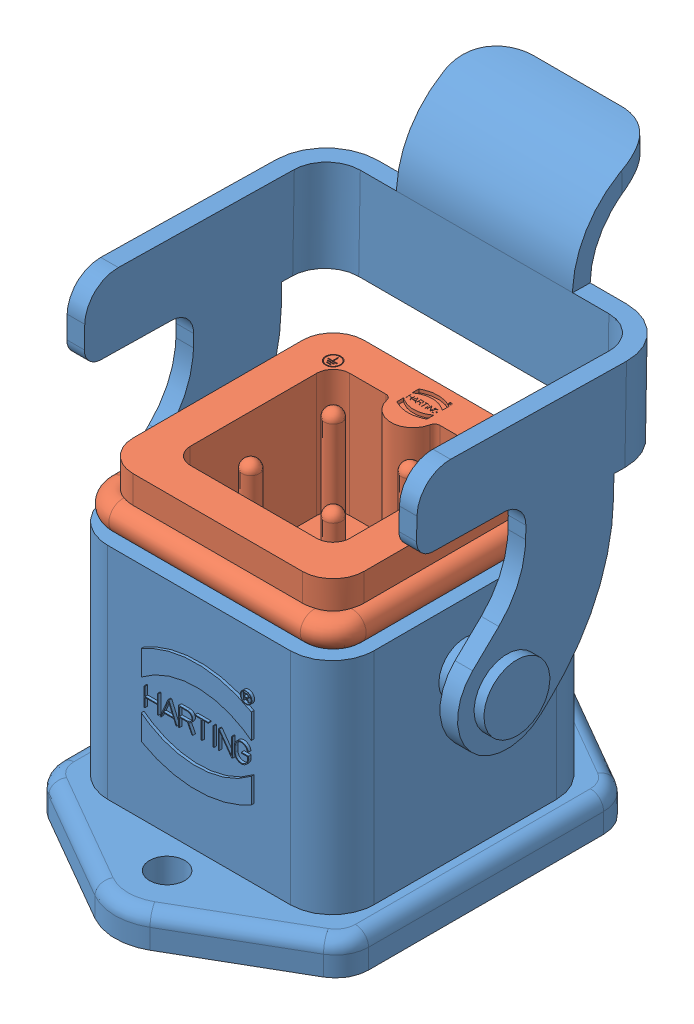
SolidWorks assembly 09200030301_assy, configuration Default. Lengths in mm.
Overall size (33.6 46.56 42.89).
2 component instances, 2 part files, 3 mates.
Components (placement in the parent):
- 09200030301-1: 09200030301 [Default] at origin size (33.6 46.56 42.89)
- 09200032611-1: 09200032611 [Default] at origin size (23.4 27.1 23.7)
Mates (geometry in assembly coordinates):
- Coincident3: coincident aligned: plane of 09200030301-1 through (0 0 0) normal (0 0 1); plane of 09200032611-1 through (0 0 0) normal (0 0 1)
- Coincident4: coincident aligned: plane of 09200030301-1 through (0 0 0) normal (1 0 0); plane of 09200032611-1 through (0 0 0) normal (1 0 0)
- Coincident5: coincident aligned: plane of 09200030301-1 through (0 0 0) normal (0 1 0); plane of 09200032611-1 through (0 0 0) normal (0 1 0)
